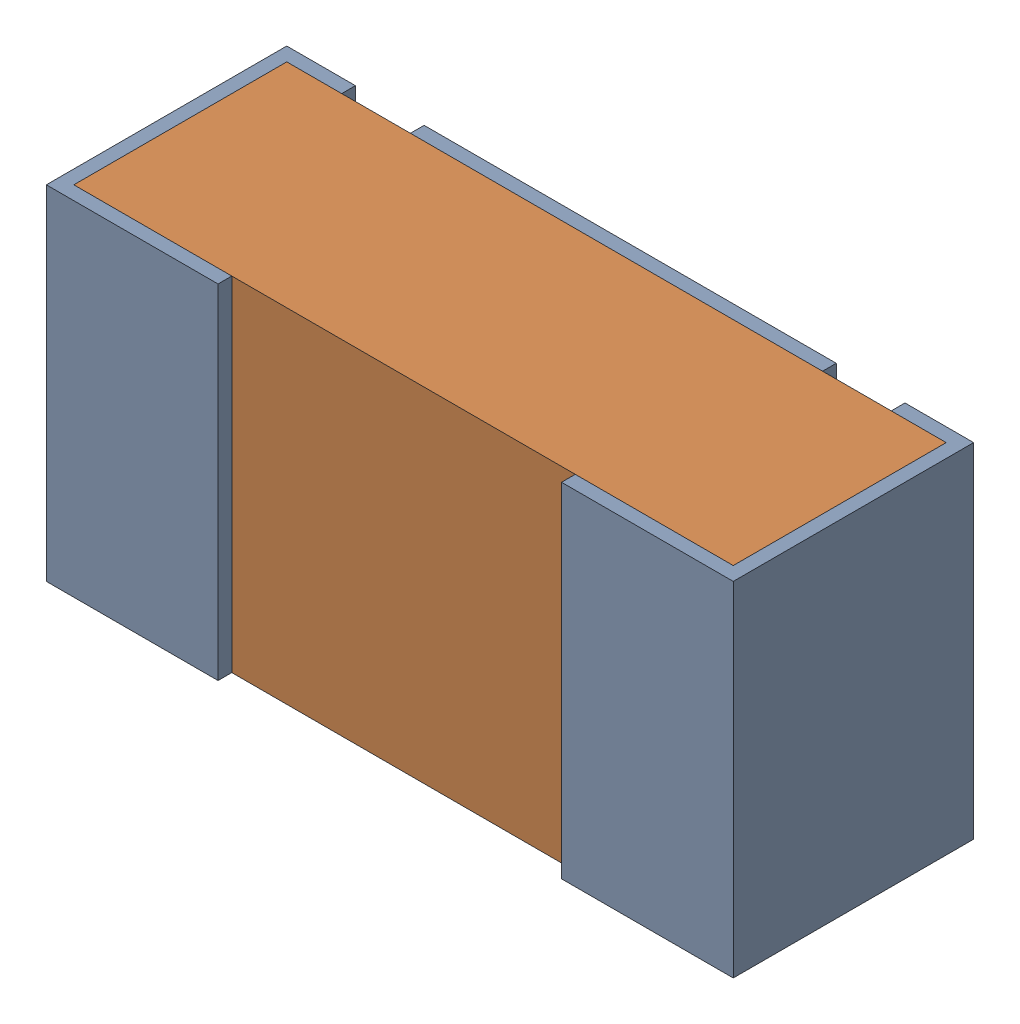
SolidWorks assembly R15, configuration Default. Lengths in mm.
Overall size (1 0.5 0.35).
3 component instances, 2 part files, 0 mates.
Components (placement in the parent):
- R15-subassembly-1-1: R15-subassembly-1 [Default] at (1.4251 -5.25 -1.6307) x (-1 0 0) z (0 -1 0) size (1 0.35 0.5)
  - 0402 resistor-1: 0402 resistor [Default] at origin size (1 0.35 0.5)
  - 0402 resistor-1-1: 0402 resistor-1 [Default] at origin size (0.96 0.31 0.5)
